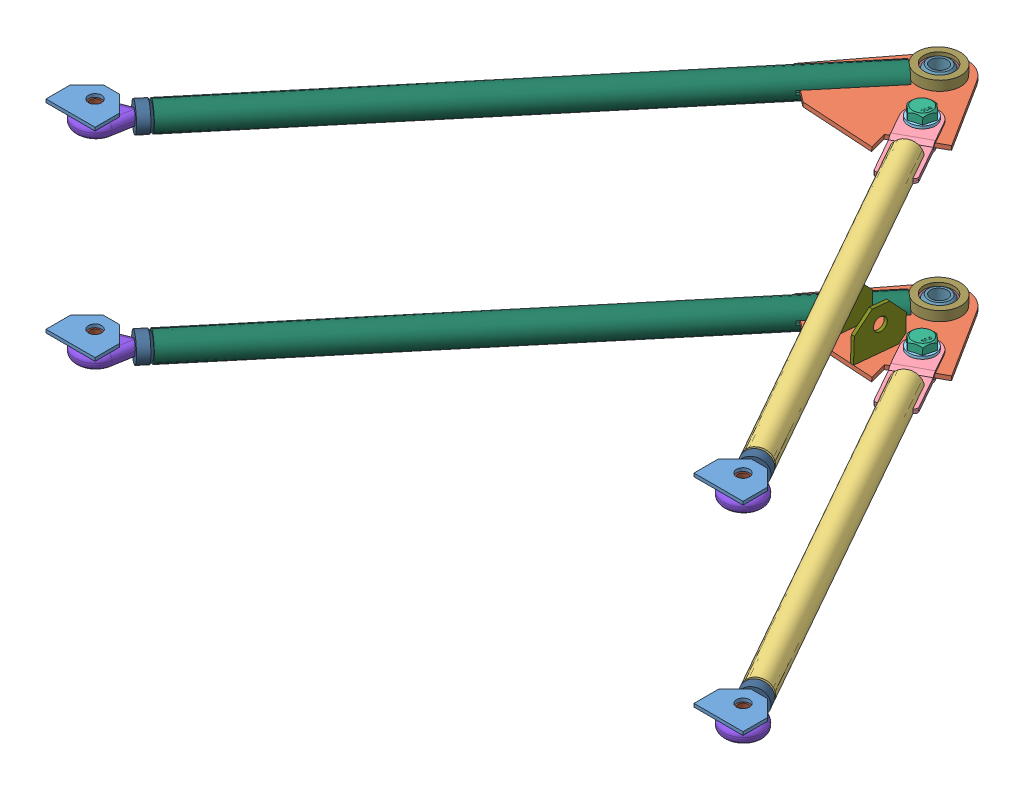
SolidWorks assembly Control Arms V5 (final), configuration Default. Lengths in mm.
Overall size (449.35 160.73 365.64).
52 component instances, 16 part files, 16 mates.
Components (placement in the parent):
- frame connectors-10: frame connectors [Default] at (-357.6393 7.7366 39.1204) size (30 2 25)
- frame connectors-11: frame connectors [Default] at (38.6473 7.7366 39.1204) size (30 2 25)
- Upper Control Arm Assembly-1: Upper Control Arm Assembly [Default] at (-132.0035 -134.0121 -251.1589) x (0.997989 0.002237 0.063355) z (-0.063395 0.035213 0.997367) size (428.79 42.68 337.86) (flexible)
  - Front Control Arm Plate-1: Front Control Arm Plate [Default] at origin size (91 2.5 76.52)
  - Rear Upper Control Arm-2: Rear Upper Control Arm [Default] at (105.6055 0 154.4308) x (-0.554844 0 -0.831954) z (0.831954 0 -0.554844) size (250 16 16)
  - Control Arm Link Plate-1: Control Arm Link Plate [Default] at (31.8652 1.25 43.6848) x (-0.554844 0 -0.831954) z (0.831954 0 -0.554844) size (54.1 2.5 20)
  - Control Arm Link Plate-2: Control Arm Link Plate [Default] at (31.8652 -1.25 43.6848) x (-0.554844 0 -0.831954) z (-0.831954 0 0.554844) size (54.1 2.5 20)
  - plain washer normal grade a_iso-1: plain washer normal grade a_iso [Washer ISO 7089 - 8] at (22.4051 2.5 29.5) x (0 -1 0) z (0.774417 0 0.632675) size (1.6 16 16)
  - 94863A205_High-Strength Class 10.9 Steel Hex Head Screw-1: 94863A205_High-Strength Class 10.9 Steel Hex Head Screw [94863A205] at (22.4051 4.1 29.5) x (0.632675 0 -0.774417) z (0 1 0) size (13 16.35 25.89)
  - 94645A111_High-Strength Steel Nylon-Insert Locknut-1: 94645A111_High-Strength Steel Nylon-Insert Locknut [94645A111] at (22.4051 -6.5 29.5) x (-0.775761 0 -0.631027) z (-0.631027 0 0.775761) size (13 8 14.93)
  - Link Insert Assembly-1: Link Insert Assembly [Default] at (151.1806 41.9532 246.62) x (0.831954 0 -0.554844) z (0 -1 0) size (24 54 13.75) (flexible)
    - Link-1: Link [Default] at (13.2343 18.3157 41.9532) size (24 54 13.75)
    - Spherical Bearing Ball-1: Spherical Bearing Ball [Default] at (13.2343 47.8157 41.9532) x (0.017677 -0.030537 0.999377) z (0.475138 -0.879204 -0.035269) size (9 13.75 13.75)
  - Control Arm Insert-1: Control Arm Insert [Default] at (162.0573 0 239.0767) x (-0.831525 0.032128 0.554558) z (0.026729 0.999484 -0.017826) size (16 25 16)
  - 8mm Spehrical Bearing Insert-1: 8mm Spehrical Bearing Insert [Default] at (188.7357 6.496 279.2864) x (0.943272 0.009583 -0.331883) z (-0.332014 0.033958 -0.942663) size (11 9 11)
  - Spherical Bearing Seat-1: Spherical Bearing Seat [Default] at (0 -0.3 0) size (30 15.1 30)
  - Wide Spherical Bearing-1: Wide Spherical Bearing [Default] at (-7.3247 -16.3877 13.3464) x (1 0 0) z (0 1 0) size (26.67 26.77 14.35) (flexible)
    - Wide Bearing Cage-1: Wide Bearing Cage [Default] at (7.3247 13.3464 16.0877) size (22 22 10.5)
    - Wide Ball-1: Wide Ball [Default] at (7.3247 13.3464 16.0877) x (-0.808404 0.588515 -0.011497) z (-0.005259 0.012311 0.99991) size (19.04 19.04 14)
  - Front Upper Control Arm-1: Front Upper Control Arm [Default] at (-100.6334 0 146.8287) x (0.559193 0 -0.829038) z (0.829038 0 0.559193) size (330 16 16)
  - Link Insert Assembly-2: Link Insert Assembly [Default] at (-191.0018 41.9532 257.1385) x (0.829038 0 0.559193) z (0 -1 0) size (24 54 13.75) (flexible)
    - Link-1: Link [Default] at (13.2343 18.3157 41.9532) size (24 54 13.75)
    - Spherical Bearing Ball-1: Spherical Bearing Ball [Default] at (13.2343 47.8157 41.9532) x (-0.021546 -0.027942 0.999377) z (-0.686519 -0.726264 -0.035107) size (9 13.75 13.75)
  - Control Arm Insert-2: Control Arm Insert [Default] at (-179.8953 0 264.3393) x (-0.82861 0.032128 -0.558904) z (0.026635 0.999484 0.017966) size (16 25 16)
  - 8mm Spehrical Bearing Insert-2: 8mm Spehrical Bearing Insert [Default] at (-206.7537 6.496 304.4089) x (-0.995546 0.005544 -0.094114) z (-0.094251 -0.034846 0.994938) size (11 9 11)
  - Push Rod Upper Control Arm Bracket-1: Push Rod Upper Control Arm Bracket [Default] at (10.7762 13.75 44.5) x (0 0 1) z (0 -1 0) size (30 2 25)
  - Push Rod Upper Control Arm Bracket-2: Push Rod Upper Control Arm Bracket [Default] at (-11.2238 13.75 44.5) x (0 0 1) z (0 -1 0) size (30 2 25)
- frame connectors-14: frame connectors [Default] at (-357.6393 -114.2634 39.1204) size (30 2 25)
- frame connectors-15: frame connectors [Default] at (38.6473 -114.2634 39.1204) size (30 2 25)
- Lower Control Arm Assembly-4: Lower Control Arm Assembly [Default] at (-132.0035 -12.0121 -251.1589) x (0.997989 0.002237 0.063355) z (-0.063395 0.035213 0.997367) size (428.79 25.89 337.86) (flexible)
  - Front Control Arm Plate-1: Front Control Arm Plate [Default] at origin size (91 2.5 76.52)
  - Rear Upper Control Arm-2: Rear Upper Control Arm [Default] at (105.6055 0 154.4308) x (-0.554844 0 -0.831954) z (0.831954 0 -0.554844) size (250 16 16)
  - Control Arm Link Plate-1: Control Arm Link Plate [Default] at (31.8652 1.25 43.6848) x (-0.554844 0 -0.831954) z (0.831954 0 -0.554844) size (54.1 2.5 20)
  - Control Arm Link Plate-2: Control Arm Link Plate [Default] at (31.8652 -1.25 43.6848) x (-0.554844 0 -0.831954) z (-0.831954 0 0.554844) size (54.1 2.5 20)
  - plain washer normal grade a_iso-1: plain washer normal grade a_iso [Washer ISO 7089 - 8] at (22.4051 2.5 29.5) x (0 -1 0) z (0.774417 0 0.632675) size (1.6 16 16)
  - 94863A205_High-Strength Class 10.9 Steel Hex Head Screw-1: 94863A205_High-Strength Class 10.9 Steel Hex Head Screw [94863A205] at (22.4051 4.1 29.5) x (0.632675 0 -0.774417) z (0 1 0) size (13 16.35 25.89)
  - 94645A111_High-Strength Steel Nylon-Insert Locknut-1: 94645A111_High-Strength Steel Nylon-Insert Locknut [94645A111] at (22.4051 -6.5 29.5) x (-0.783807 0 -0.621005) z (-0.621005 0 0.783807) size (13 8 14.93)
  - Link Insert Assembly-1: Link Insert Assembly [Default] at (151.1806 41.9532 246.62) x (0.831954 0 -0.554844) z (0 -1 0) size (24 54 13.75) (flexible)
    - Link-1: Link [Default] at (13.2343 18.3157 41.9532) size (24 54 13.75)
    - Spherical Bearing Ball-1: Spherical Bearing Ball [Default] at (13.2343 47.8157 41.9532) x (0.017677 -0.030537 0.999377) z (-0.222901 0.974258 0.033712) size (9 13.75 13.75)
  - Control Arm Insert-1: Control Arm Insert [Default] at (162.0573 0 239.0767) x (-0.831525 0.032128 0.554558) z (0.026729 0.999484 -0.017826) size (16 25 16)
  - 8mm Spehrical Bearing Insert-1: 8mm Spehrical Bearing Insert [Default] at (188.7357 6.496 279.2864) x (0.571827 -0.030167 0.81982) z (0.820372 0.018302 -0.571538) size (11 9 11)
  - Spherical Bearing Seat-1: Spherical Bearing Seat [Default] at (0 -0.3 0) size (30 15.1 30)
  - Wide Spherical Bearing-1: Wide Spherical Bearing [Default] at (-7.3247 -16.3877 13.3464) x (1 0 0) z (0 1 0) size (26.26 26.36 14.35) (flexible)
    - Wide Bearing Cage-1: Wide Bearing Cage [Default] at (7.3247 13.3464 16.0877) size (22 22 10.5)
    - Wide Ball-1: Wide Ball [Default] at (7.3247 13.3464 16.0877) x (-0.852078 0.523301 -0.010924) z (-0.005259 0.012311 0.99991) size (19.04 19.04 14)
  - Front Upper Control Arm-1: Front Upper Control Arm [Default] at (-100.6334 0 146.8287) x (0.559193 0 -0.829038) z (0.829038 0 0.559193) size (330 16 16)
  - Link Insert Assembly-2: Link Insert Assembly [Default] at (-191.0018 41.9532 257.1385) x (0.829038 0 0.559193) z (0 -1 0) size (24 54 13.75) (flexible)
    - Link-1: Link [Default] at (13.2343 18.3157 41.9532) size (24 54 13.75)
    - Spherical Bearing Ball-1: Spherical Bearing Ball [Default] at (13.2343 47.8157 41.9532) x (-0.021546 -0.027942 0.999377) z (-0.746659 -0.664303 -0.034671) size (9 13.75 13.75)
  - Control Arm Insert-2: Control Arm Insert [Default] at (-179.8953 0 264.3393) x (-0.82861 0.032128 -0.558904) z (0.026635 0.999484 0.017966) size (16 25 16)
  - 8mm Spehrical Bearing Insert-2: 8mm Spehrical Bearing Insert [Default] at (-206.7537 6.496 304.4089) x (-0.997267 0.00483 -0.07372) z (-0.073844 -0.034952 0.996657) size (11 9 11)
Mates (geometry in assembly coordinates):
- Concentric18: concentric aligned: cylinder of frame connectors-10 through (-357.6393 8.7366 39.1204) axis (0 -1 0) radius 4; cylinder of frame connectors-14 through (-357.6393 -113.2634 39.1204) axis (0 -1 0) radius 4
- Coincident27: coincident aligned: plane of frame connectors-10 through (-372.6393 8.7366 54.1204) normal (0 0 1); plane of frame connectors-14 through (-372.6393 -113.2634 54.1204) normal (0 0 1)
- Distance2: distance = 120 mm anti-aligned: plane of frame connectors-14 through (-357.6393 -113.2634 39.1204) normal (0 1 0); plane of frame connectors-10 through (-357.6393 6.7366 39.1204) normal (0 -1 0)
- Concentric19: concentric aligned: cylinder of Upper Control Arm Assembly-1/8mm Spehrical Bearing Insert-2 through (-357.6393 -117.2634 39.1204) axis (0 -1 0) radius 3; cylinder of frame connectors-14 through (-357.6393 -113.2634 39.1204) axis (0 -1 0) radius 4
- Coincident29: coincident anti-aligned: plane of Upper Control Arm Assembly-1/8mm Spehrical Bearing Insert-2 through (-352.2076 -115.2634 39.9847) normal (0 1 0); plane of frame connectors-14 through (-357.6393 -115.2634 39.1204) normal (0 -1 0)
- Coincident30: coincident aligned: plane of frame connectors-14 through (-372.6393 -113.2634 54.1204) normal (0 0 1); plane of frame connectors-15 through (23.6473 -113.2634 54.1204) normal (0 0 1)
- Coincident31: coincident aligned: plane of frame connectors-14 through (-357.6393 -113.2634 39.1204) normal (0 1 0); plane of frame connectors-15 through (38.6473 -113.2634 39.1204) normal (0 1 0)
- Concentric21: concentric aligned: cylinder of frame connectors-10 through (-357.6393 8.7366 39.1204) axis (0 -1 0) radius 4; circle of Lower Control Arm Assembly-4/8mm Spehrical Bearing Insert-2
- Coincident33: coincident anti-aligned: plane of frame connectors-10 through (-357.6393 6.7366 39.1204) normal (0 -1 0); plane of Lower Control Arm Assembly-4/8mm Spehrical Bearing Insert-2 through (-352.191 6.7366 39.8732) normal (0 1 0)
- Coincident38: coincident anti-aligned: plane of Upper Control Arm Assembly-1/8mm Spehrical Bearing Insert-1 through (33.354 -115.2634 40.6141) normal (0 1 0); plane of frame connectors-15 through (38.6473 -115.2634 39.1204) normal (0 -1 0)
- Concentric22: concentric aligned: cylinder of Upper Control Arm Assembly-1/8mm Spehrical Bearing Insert-1 through (38.6473 -117.2634 39.1204) axis (0 -1 0) radius 3; cylinder of frame connectors-15 through (38.6473 -113.2634 39.1204) axis (0 -1 0) radius 4
- Coincident39: coincident aligned: plane of frame connectors-10 through (-372.6393 8.7366 54.1204) normal (0 0 1); plane of frame connectors-11 through (23.6473 8.7366 54.1204) normal (0 0 1)
- Coincident40: coincident aligned: plane of frame connectors-10 through (-357.6393 8.7366 39.1204) normal (0 1 0); plane of frame connectors-11 through (38.6473 8.7366 39.1204) normal (0 1 0)
- Concentric23: concentric aligned: cylinder of frame connectors-11 through (38.6473 8.7366 39.1204) axis (0 -1 0) radius 4; cylinder of Lower Control Arm Assembly-4/8mm Spehrical Bearing Insert-1 through (38.6473 4.7366 39.1204) axis (0 -1 0) radius 3
- Coincident41: coincident anti-aligned: plane of frame connectors-11 through (38.6473 6.7366 39.1204) normal (0 -1 0); plane of Lower Control Arm Assembly-4/8mm Spehrical Bearing Insert-1 through (35.7944 6.7366 34.4182) normal (0 1 0)
- Parallel9: parallel aligned: plane of Upper Control Arm Assembly-1/Front Control Arm Plate-1 through (-132.0025 -132.7635 -251.2195) normal (0 0.999377 -0.035284); plane of Lower Control Arm Assembly-4/Front Control Arm Plate-1 through (-132.0025 -10.7635 -251.2195) normal (0 0.999377 -0.035284)
